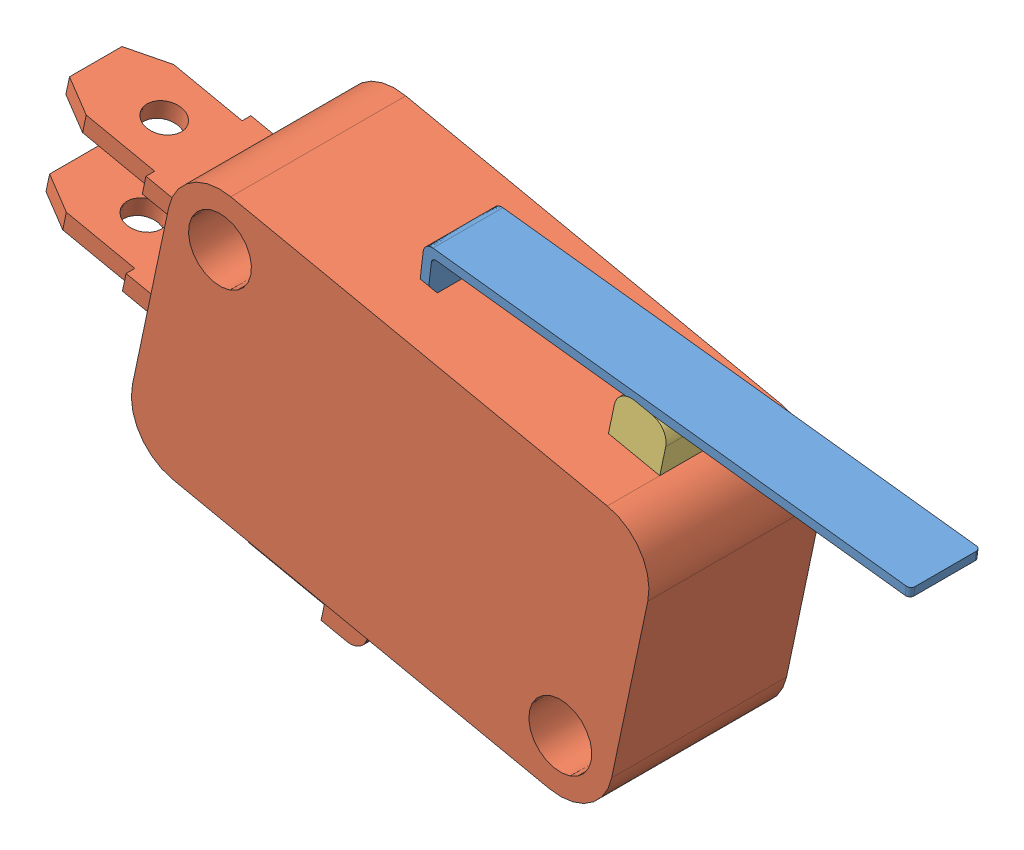
SolidWorks assembly micro switch, configuration Predeterminado. Lengths in mm.
Overall size (51.53 26.23 10).
3 component instances, 3 part files, 6 mates.
Components (placement in the parent):
- palanca switch-1: palanca switch [Predeterminado] at (152.408 -13.1757 63.6721) x (0.993061 -0.117596 0) z (0 0 1) size (28 5 6)
- switch-1: switch [Predeterminado] at (-58.9157 -3.0205 31.2303) x (-0.978425 0.206604 0) z (-0.206604 -0.978425 0) size (37 10 19)
- boton-1: boton [Predeterminado] at (0.7172 5.2123 24.2303) x (-0.978425 0.206604 0) z (0 0 -1) size (3 4 4)
Mates (geometry in assembly coordinates):
- Coincidente1: coincident anti-aligned: plane of switch-1 through (0.1709 2.6251 28.2303) normal (-0.978425 0.206604 0); plane of boton-1 through (1.5436 9.126 28.2303) normal (0.978425 -0.206604 0)
- Coincidente2: coincident anti-aligned: plane of switch-1 through (-2.7644 3.2449 28.2303) normal (0 0 -1); plane of boton-1 through (-1.3917 9.7458 28.2303) normal (0 0 1)
- Concéntrica1: concentric anti-aligned: cylinder of palanca switch-1 through (-12.7796 6.6372 29.2303) axis (0 0 -1) radius 0.25; cylinder of switch-1 through (-12.7796 6.6372 23.2303) axis (0 0 1) radius 0.25
- Coincidente3: coincident anti-aligned: plane of palanca switch-1 through (-11.9728 11.3249 28.2303) normal (0 0 1); plane of switch-1 through (-13.3205 6.4959 28.2303) normal (0 0 -1)
- Ángulo límite2: limit planar angle = 1.480563 rad anti-aligned: plane of palanca switch-1 through (-12.4693 11.3837 28.2303) normal (-0.993061 0.117596 0); plane of switch-1 through (0.9973 6.5388 21.2303) normal (0.206604 0.978425 0)
- Tangente2: tangent anti-aligned: plane of palanca switch-1 through (15.2776 7.5945 28.2303) normal (-0.117596 -0.993061 0); cylinder of boton-1 through (0.3586 8.3542 24.2303) axis (0 0 1) radius 1
